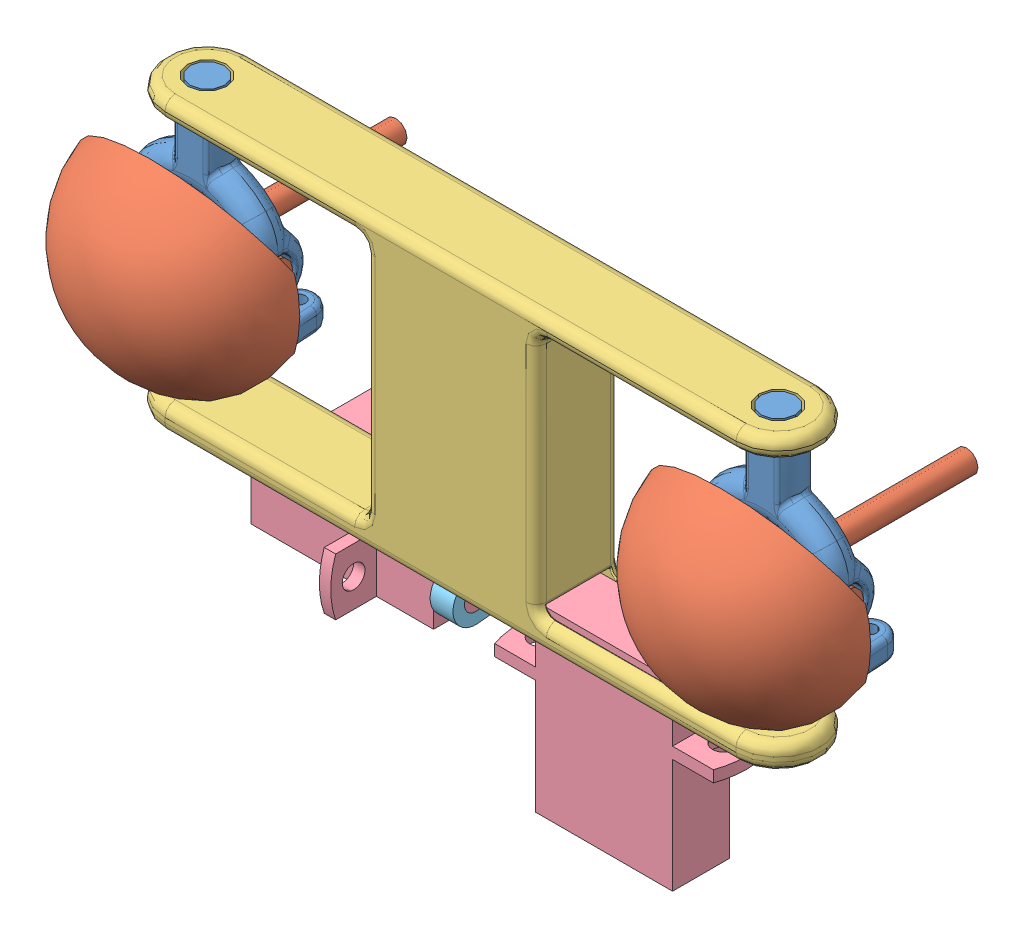
SolidWorks assembly gimbal, configuration Default. Lengths in mm.
Overall size (69.7 39 26.5).
11 component instances, 5 part files, 19 mates.
Components (placement in the parent):
- whole_outer-1: whole_outer [Default] at (-87.4775 11.3635 38.4405) size (12.4 25.4 12.5)
- gimbal_test-1: gimbal_test [Default] at (-87.4775 11.3635 38.4405) size (19.7 17.32 26.5)
- gimbal_test-2: gimbal_test [Default] at (-37.4775 11.3635 38.4405) size (19.7 17.32 26.5)
- whole_outer-2: whole_outer [shorter] at (-37.4775 11.3635 38.4405) size (12.4 25.4 12.5)
- Part2-1: Part2 [Default] at (-37.4775 0.8635 38.4405) x (-1 0 0) z (0 -1 0) size (57.4 7.4 25.4)
- servo-1: servo [+90] at (30.4295 -37.0518 16.8829) size (20 18 13.5)
  - mini_servo-1: mini_servo [Default] at (-80.6559 31.9153 21.5576) size (20 18 5)
  - Part3^servo-1: Part3^servo [Default] at (-76.3582 39.9153 17.2599) x (0 0 1) z (0 1 0) size (13 4 2) (virtual)
- servo-2: servo [Default] at (-103.8683 -25.5942 114.7987) x (0 0 1) z (0 1 0) size (20 18 5)
  - mini_servo-1: mini_servo [Default] at (-80.6559 31.9153 21.5576) size (20 18 5)
  - Part3^servo-1: Part3^servo [Default] at (-80.6559 39.9153 21.5576) x (1 0 0) z (0 1 0) size (13 4 2) (virtual)
Mates (geometry in assembly coordinates):
- Width1: width anti-aligned: plane of whole_outer-1 through (-84.2775 11.3635 38.4405) normal (-1 0 0); plane of whole_outer-1 through (-90.6775 11.3635 38.4405) normal (1 0 0); plane of gimbal_test-1 through (-84.4775 11.3635 38.4405) normal (1 0 0); plane of gimbal_test-1 through (-90.4775 11.3635 38.4405) normal (-1 0 0)
- Concentric1: concentric aligned: cylinder of whole_outer-1 through (-89.0858 11.3635 38.4405) axis (1 0 0) radius 1.7; cylinder of gimbal_test-1 through (-93.4775 11.3635 38.4405) axis (1 0 0) radius 1.5
- Concentric2: concentric anti-aligned: cylinder of whole_outer-1 through (-89.0858 11.3635 38.4405) axis (1 0 0) radius 1.7; cylinder of whole_outer-2 through (-35.8692 11.3635 38.4405) axis (-1 0 0) radius 1.7
- Width2: width anti-aligned: plane of whole_outer-2 through (-40.6775 11.3635 38.4405) normal (1 0 0); plane of whole_outer-2 through (-34.2775 11.3635 38.4405) normal (-1 0 0); plane of gimbal_test-2 through (-40.4775 11.3635 38.4405) normal (-1 0 0); plane of gimbal_test-2 through (-34.4775 11.3635 38.4405) normal (1 0 0)
- Concentric3: concentric aligned: cylinder of gimbal_test-2 through (-43.4775 11.3635 38.4405) axis (1 0 0) radius 1.5; cylinder of whole_outer-2 through (-39.0858 11.3635 38.4405) axis (1 0 0) radius 1.7
- Coincident1: coincident aligned: plane of whole_outer-1 through (-87.4775 23.8635 38.4405) normal (0 1 0); plane of whole_outer-2 through (-37.4775 23.8635 38.4405) normal (0 1 0)
- Distance1: distance = 50 mm aligned: plane of whole_outer-1 through (-87.4775 11.3635 38.4405) normal (1 0 0); plane of whole_outer-2 through (-37.4775 11.3635 38.4405) normal (1 0 0)
- InPlace1: in place: plane of ? through (-35.4775 2.3135 38.4405) normal (0 1 0); plane of ? through (0 2.3135 0) normal (0 1 0); moOrthogonalPlaneRef_w of ? through (-35.4775 2.3135 38.4405) normal (0 1 0); plane of ? through (0 2.3135 0) normal (0 0 -1); plane of ? through (-35.4775 2.3135 38.4405) normal (0 1 0); unknown of ?; plane of ? through (-37.4775 0.8635 38.4405) normal (0 -1 0); unknown of Part2-1
- Coincident2: coincident aligned: plane of whole_outer-2; plane of Part2-1
- Coincident3: coincident aligned: moOrthogonalPlaneRef_w of whole_outer-2 through (-37.4775 0.8635 38.4405) normal (0 0 -1); plane of Part2-1
- Coincident4: coincident anti-aligned: moOrthogonalPlaneRef_w of whole_outer-2; plane of Part2-1
- Parallel1: parallel aligned: line of gimbal_test-1 through (-87.4775 11.3635 21.9405) axis (0 0 1); line of gimbal_test-2 through (-37.4775 11.3635 21.9405) axis (0 0 1)
- Parallel5: parallel aligned: plane of Part2-1 through (-37.4775 -1.5365 38.4405) normal (0 -1 0); plane of servo-1/mini_servo-1 through (-50.2264 -15.1365 38.4405) normal (0 -1 0)
- Coincident11: coincident: line of servo-1/Part3^servo-1 through (-45.9286 0.8635 38.4405) axis (0 1 0); plane of assembly
- Parallel7: parallel aligned: line of servo-2/Part3^servo-1 through (-65.953 -4.0365 38.4405) axis (1 0 0)
- Coincident15: coincident: line of servo-2/Part3^servo-1 through (-65.953 -4.0365 38.4405) axis (1 0 0)
- Coincident17: coincident anti-aligned: plane of Part2-1 through (-37.4775 -1.5365 38.4405) normal (0 -1 0); plane of servo-2/mini_servo-1 through (-81.953 -1.5365 40.1427) normal (0 1 0)
- Parallel8: parallel aligned: line of gimbal_test-2 through (-37.4775 11.3635 21.9405) axis (0 0 1); line of servo-1/Part3^servo-1 through (-45.9286 2.8635 28.4405) axis (0 0 1)
- Coincident20: coincident aligned: plane of whole_outer-2 through (-37.4775 2.8635 38.4405) normal (0 1 0); plane of servo-1/Part3^servo-1 through (-45.9286 2.8635 38.4405) normal (0 1 0)
